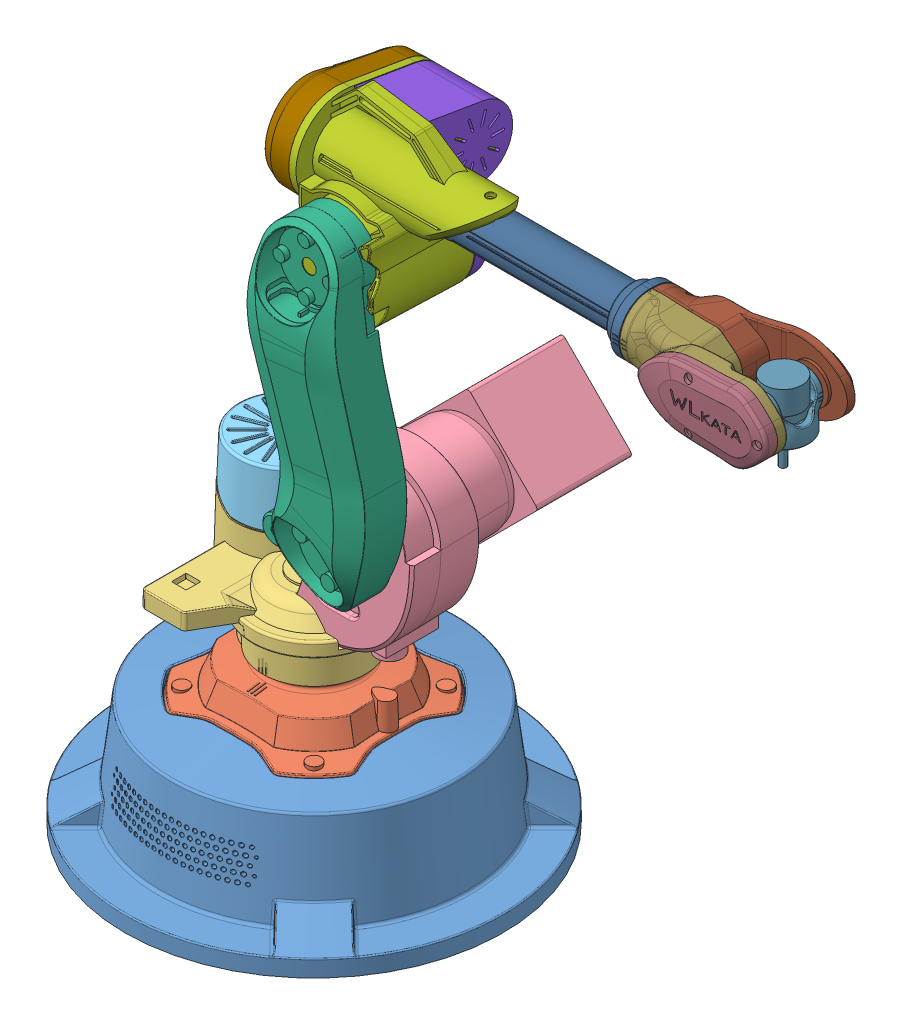
SolidWorks assembly WLKATA Mirobot, configuration 默认. Lengths in mm.
Overall size (295 290.13 160).
19 component instances, 14 part files, 15 mates.
Components (placement in the parent):
- Mirobot_Base-2: Mirobot_Base [默认] at (0.266 25.164 -160.0008) size (160 67.39 160)
  - 01固定座底壳-1: 01固定座底壳 [默认] at (-0.266 20.3702 160.0008) x (1 0 0) z (0 1 0) size (160 160 50.86)
  - 03连接底座-2: 03连接底座 [默认] at (-50.0172 22.0959 160.0008) x (0 0 1) z (0 1 0) size (80.02 80.02 20.82)
- Mirobot_Link1-2: Mirobot_Link1 [默认] at (-11.634 88.7456 -76.4615) size (114.93 90.38 115.48)
  - 04旋转底座-2: 04旋转底座 [默认] at (0.2776 -9.246 77.9265) x (1 0 0) z (0 1 0) size (75.38 77.6 46.2)
  - 05支撑底座-1: 05支撑底座 [默认] at (37.6662 26.4117 76.5499) x (-1 0 0) z (0 0 -1) size (60.2 76.87 97.54)
  - 1关节盖-2: 1关节盖 [默认] at (15.6589 10.9772 42.2526) x (0.5 0 0.866025) z (0 1 0) size (41.83 41.33 23.09)
- Mirobot_Link2-1: Mirobot_Link2 [Default] at (29.6872 234.9996 15.5) x (0.999968 0.007966 0) z (0 0 1) size (79.48 149.11 37)
  - QN1903.02—01大臂V2-1: QN1903.02—01大臂V2 [默认] x (-0.113383 0.993551 0) z (0.993551 0.113383 0) size (142.8 37 63.7)
- Mirobot_Link3-1: Mirobot_Link3 [默认] at (29.6872 234.6196 18.4437) size (167.71 84.01 80.56)
  - 10中关节-1: 10中关节 [默认] at (15.2267 9.3067 -18.44) x (0 -1 0) z (0 0 1) size (75.61 74.62 74.94)
  - 11中关节盖-1: 11中关节盖 [默认] at (-0.0018 -43.4251 -31.355) x (1 0 0) z (0 0 -1) size (42.77 67.95 38.74)
  - 16中关节后盖-1: 16中关节后盖 [默认] at (-20.6118 -17.635 -30.2843) x (0 -0.001809 0.999998) z (-1 0 0) size (76.1 71.71 60.93)
  - 12中关节管-3: 12中关节管 [默认] at (80.5287 -4.4953 -18.44) x (0 -1 0) z (0 0 1) size (25.84 105.18 28.04)
- Mirobot_Link4-1: Mirobot_Link4 [默认] at (178.5076 251.5286 -82.889) x (1 0 0) z (0 0.000032 1) size (73.76 38.7 46.95)
  - 13小臂左-1: 13小臂左 [默认] at (-50.6649 3.4687 82.8928) x (0 1 0) z (0 0 -1) size (37.72 71.11 23.56)
  - 13小臂右-1: 13小臂右 [默认] at (-50.3902 3.4629 82.8928) x (0 1 0) z (0 0 1) size (32.12 73.76 17.35)
  - 14小臂右盖-2: 14小臂右盖 [默认] at (49.5493 33.4629 99.9428) x (0 1 0) z (0 0 1) size (32.23 55.01 6.34)
- Mirobot_Link5-1: Mirobot_Link5 [默认] at (223.5411 240.2074 0.1146) x (0 0 -1) z (0 -1 0) size (24.43 20.27 33.48)
Mates (geometry in assembly coordinates):
- 同心2: concentric: cylinder of assembly; cylinder of Mirobot_Base-2/01固定座底壳-1 through (0 0 0) axis (0 1 0) radius 80; point of assembly
- 重合3: coincident: plane of Mirobot_Base-2/01固定座底壳-1 through (0 0 0) normal (0 -1 0)
- 同心3: concentric aligned: cylinder of Mirobot_Base-2/03连接底座-2 through (0 47 0) axis (0 -1 0) radius 19; cone of Mirobot_Link1-2/04旋转底座-2 through (0 87.4496 0) axis (0 -1 0)
- 重合5: coincident anti-aligned: plane of Mirobot_Base-2/03连接底座-2 through (0 67.3896 0) normal (0 1 0); plane of Mirobot_Link1-2/04旋转底座-2 through (0 67.3896 0) normal (0 -1 0)
- 平行1: parallel aligned: plane of Mirobot_Link1-2/05支撑底座-1 through (-27.7128 93.7996 12) normal (0 0 1); plane of assembly through (0 0 0) normal (0 0 1)
- 同心4: concentric anti-aligned: cylinder of Mirobot_Link1-2/05支撑底座-1 through (29.6872 126.9996 22) axis (0 0 -1) radius 3; cylinder of ? through (29.6872 126.9996 22.429) axis (0 0 1) radius 4
- 平行3: parallel anti-aligned: plane of Mirobot_Base-2/01固定座底壳-1 through (-56.0779 22.6591 0) normal (-1 0 0); plane of Mirobot_Link3-1/12中关节管-3 through (142.9055 254.9999 0.0037) normal (1 0 0)
- 同心8: concentric anti-aligned: cylinder of Mirobot_Link3-1/12中关节管-3 through (110.0555 254.9999 0.0037) axis (1 0 0) radius 8.65; cylinder of Mirobot_Link4-1/13小臂左-1 through (172.9055 254.9999 0.0037) axis (-1 0 0) radius 10
- 重合19: coincident anti-aligned: plane of Mirobot_Link3-1/12中关节管-3 through (142.9055 254.9999 0.0037) normal (1 0 0); plane of Mirobot_Link4-1/13小臂左-1 through (142.9055 254.9942 -0.9963) normal (-1 0 0)
- 同心12: concentric aligned: cylinder of Mirobot_Link2-1/QN1903.02—01大臂V2-1 through (29.6872 234.9996 31.7737) axis (0 0 -1) radius 3; cylinder of Mirobot_Link3-1/10中关节-1 through (29.6872 234.9996 31.4437) axis (0 0 -1) radius 3
- 平行4: parallel anti-aligned: plane of Mirobot_Base-2/01固定座底壳-1 through (-56.0779 22.6591 0) normal (-1 0 0); plane of Mirobot_Link2-1/QN1903.02—01大臂V2-1 through (29.6872 215.5914 35.4937) normal (1 0 0)
- 重合25: coincident anti-aligned: plane of Mirobot_Link2-1/QN1903.02—01大臂V2-1 through (29.6872 234.9996 18.4437) normal (0 0 -1); plane of Mirobot_Link3-1/10中关节-1 through (29.6855 235.0099 18.4437) normal (0 0 1)
- 同心13: concentric aligned: cylinder of Mirobot_Link1-2/05支撑底座-1 through (29.6872 126.9996 22) axis (0 0 -1) radius 3; cylinder of Mirobot_Link2-1/QN1903.02—01大臂V2-1 through (29.6872 126.9996 27.4953) axis (0 0 -1) radius 3
- 重合26: coincident anti-aligned: plane of Mirobot_Link1-2/05支撑底座-1 through (-27.7128 93.7996 12) normal (0 0 1); plane of Mirobot_Link2-1/QN1903.02—01大臂V2-1 through (29.6872 126.9996 12) normal (0 0 -1)
- 同心15: concentric aligned: cylinder of Mirobot_Link4-1/13小臂左-1 through (198.6655 254.9937 -17.2916) axis (0 0.000032 1) radius 3; cylinder of Mirobot_Link5-1 through (198.6655 254.9938 -13.3876) axis (0 0.000032 1) radius 3
